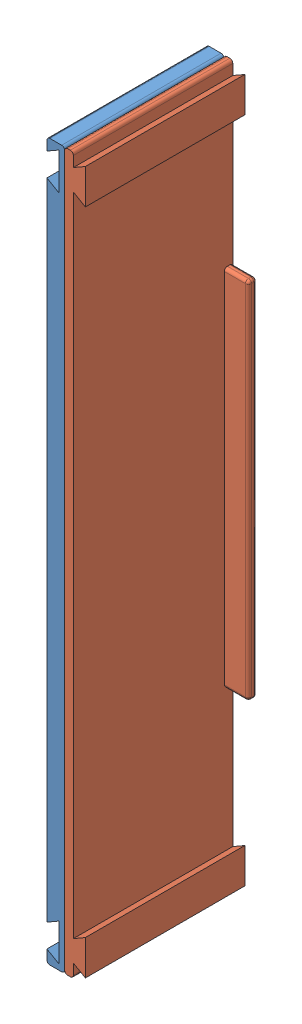
SolidWorks assembly middle part, configuration Default. Lengths in mm.
Overall size (16.8 238 53).
2 component instances, 2 part files, 3 mates.
Components (placement in the parent):
- side_part_female-1: side_part_female [Default] at (-42.9031 106.5242 211.5) size (5.9 238 53)
- side_part_male-1: side_part_male [Default] at (-34.1031 -131.4758 211.5) x (-1 0 0) z (0 0 1) size (10.9 238 53)
Mates (geometry in assembly coordinates):
- Coincident1: coincident: plane of side_part_female-1 through (-37.0031 97.8586 264.5) normal (1 0 0); plane of side_part_male-1 through (-37.0031 -124.9689 264.5) normal (-1 0 0)
- Coincident2: coincident: plane of side_part_female-1 through (-42.9031 106.5242 264.5) normal (0 0 1); plane of side_part_male-1 through (-34.1031 -132.4276 264.5) normal (0 0 1)
- Coincident3: coincident aligned: plane of side_part_female-1 through (-37.0031 106.5242 264.5) normal (0 1 0); plane of side_part_male-1 through (-37.0031 106.5242 264.5) normal (0 1 0)
